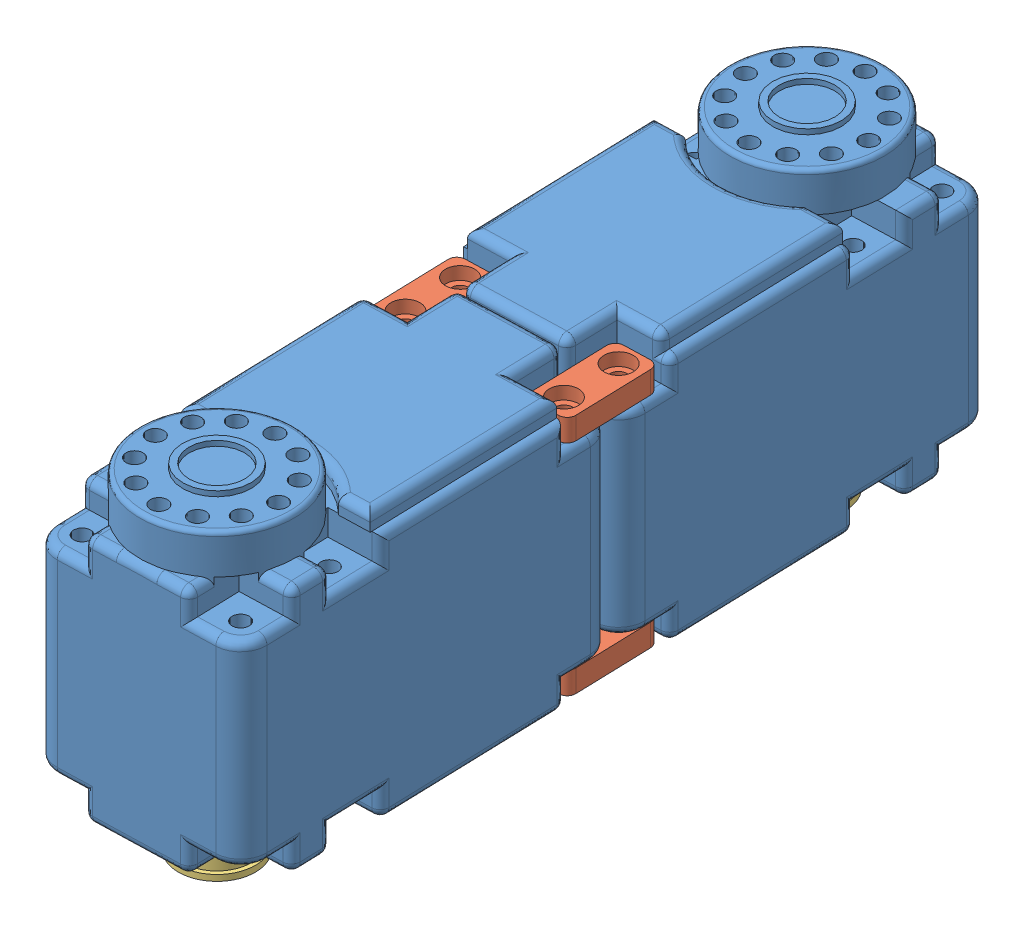
SolidWorks assembly arm, configuration Default. Lengths in mm.
Overall size (26.73 39.2 91.28).
8 component instances, 3 part files, 18 mates.
Components (placement in the parent):
- herkulex_motor-1: herkulex_motor [Default] at (3.1521 53.1425 38.0968) x (0.999543 0 -0.030221) z (0.030221 0 0.999543) size (24 34.2 45)
- line loint-1: line loint [Default] at (12.8371 53.5425 60.6144) x (-0.030221 0 -0.999543) z (0.999543 0 -0.030221) size (11 2.6 5)
- line loint-2: line loint [Default] at (-5.1547 53.5425 61.1584) x (-0.030221 0 -0.999543) z (0.999543 0 -0.030221) size (11 2.6 5)
- line loint-3: line loint [Default] at (12.8371 79.1425 60.6144) x (-0.030221 0 -0.999543) z (0.999543 0 -0.030221) size (11 2.6 5)
- line loint-4: line loint [Default] at (-5.1547 79.1425 61.1584) x (-0.030221 0 -0.999543) z (0.999543 0 -0.030221) size (11 2.6 5)
- support-1: support [Default] at (2.7653 53.6425 25.3027) x (0 -1 0) z (0 0 1) size (5.5 9 9)
- herkulex_motor-3: herkulex_motor [Default] at (4.5302 53.1425 83.676) x (-0.999543 0 0.030221) z (-0.030221 0 -0.999543) size (24 34.2 45)
- support-2: support [Default] at (4.917 53.6425 96.4701) x (0 -1 0) z (0 0 1) size (5.5 9 9)
Mates (geometry in assembly coordinates):
- Concentric1: concentric aligned: cylinder of herkulex_motor-1 through (12.7373 53.1425 57.3159) axis (0 1 0) radius 1; cylinder of line loint-1 through (12.7373 54.6425 57.3159) axis (0 1 0) radius 1.7
- Coincident4: coincident anti-aligned: plane of herkulex_motor-1 through (3.1521 56.1425 38.0968) normal (0 -1 0); plane of line loint-1 through (12.8371 56.1425 60.6144) normal (0 1 0)
- Concentric3: concentric anti-aligned: cylinder of herkulex_motor-1 through (-5.2545 53.1425 57.8599) axis (0 1 0) radius 1; cylinder of line loint-2 through (-5.2545 56.1425 57.8599) axis (0 -1 0) radius 1
- Coincident5: coincident anti-aligned: plane of herkulex_motor-1 through (3.1521 56.1425 38.0968) normal (0 -1 0); plane of line loint-2 through (-5.1547 56.1425 61.1584) normal (0 1 0)
- Concentric5: concentric aligned: cylinder of herkulex_motor-1 through (12.7373 53.1425 57.3159) axis (0 1 0) radius 1; cylinder of line loint-3 through (12.7373 80.2425 57.3159) axis (0 1 0) radius 1.7
- Coincident6: coincident anti-aligned: plane of herkulex_motor-1 through (3.1521 79.1425 38.0968) normal (0 1 0); plane of line loint-3 through (12.8371 79.1425 60.6144) normal (0 -1 0)
- Concentric7: concentric aligned: cylinder of herkulex_motor-1 through (-5.2545 53.1425 57.8599) axis (0 1 0) radius 1; cylinder of line loint-4 through (-5.2545 80.2425 57.8599) axis (0 1 0) radius 1.7
- Coincident7: coincident anti-aligned: plane of herkulex_motor-1 through (3.1521 79.1425 38.0968) normal (0 1 0); plane of line loint-4 through (-5.1547 79.1425 61.1584) normal (0 -1 0)
- Coincident8: coincident anti-aligned: plane of herkulex_motor-1 through (2.7653 53.6425 25.3027) normal (0 -1 0); plane of support-1 through (2.7653 53.6425 25.3027) normal (0 1 0)
- Concentric8: concentric aligned: circle of herkulex_motor-1; cylinder of support-1 through (2.7653 50.1425 25.3027) axis (0 -1 0) radius 2.7
- Concentric9: concentric aligned: cylinder of line loint-2 through (-5.055 54.6425 64.4569) axis (0 1 0) radius 1.7; cylinder of herkulex_motor-3 through (-5.055 53.1425 64.4569) axis (0 1 0) radius 1
- Coincident9: coincident anti-aligned: plane of line loint-2 through (-5.1547 56.1425 61.1584) normal (0 1 0); plane of herkulex_motor-3 through (4.5302 56.1425 83.676) normal (0 -1 0)
- Coincident10: coincident aligned: plane of herkulex_motor-1 through (-8.1624 84.1425 60.9492) normal (-0.999543 0 0.030221); plane of herkulex_motor-3 through (-8.1443 84.1425 61.5489) normal (-0.999543 0 0.030221)
- Parallel2: parallel aligned: plane of line loint-3 through (15.5021 81.7425 66.0364) normal (0.999543 0 -0.030221); plane of herkulex_motor-3 through (15.8447 84.1425 60.8236) normal (0.999543 0 -0.030221)
- Coincident12: coincident aligned: plane of line loint-1 through (15.5021 56.1425 66.0364) normal (0.999543 0 -0.030221); plane of line loint-3 through (15.5021 81.7425 66.0364) normal (0.999543 0 -0.030221)
- Coincident13: coincident aligned: plane of line loint-2 through (-7.4874 56.1425 66.7314) normal (-0.999543 0 0.030221); plane of line loint-4 through (-7.4874 81.7425 66.7314) normal (-0.999543 0 0.030221)
- Concentric10: concentric anti-aligned: cylinder of herkulex_motor-3 through (4.917 63.1425 96.4701) axis (0 -1 0) radius 1.475; cylinder of support-2 through (4.917 43.6425 96.4701) axis (0 1 0) radius 1.5
- Coincident14: coincident anti-aligned: plane of herkulex_motor-3 through (4.917 53.6425 96.4701) normal (0 -1 0); plane of support-2 through (4.917 53.6425 96.4701) normal (0 1 0)
